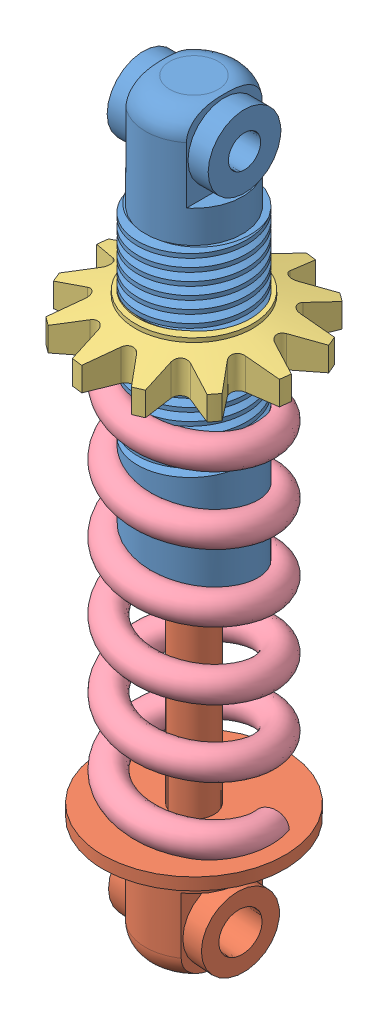
SolidWorks assembly shock absorber ass, configuration Default. Lengths in mm.
Overall size (66.19 187.81 66.19).
4 component instances, 4 part files, 6 mates.
Components (placement in the parent):
- top rod-1: top rod [Default] at (42.5756 -6.4521 89.0475) size (28.04 109.38 28.04)
- base-1: base [Default] at (42.5756 -56.4284 89.0475) x (0.997016 0 0.077201) z (-0.077201 0 0.997016) size (45 101.45 45)
- ring-1: ring [Default] at (42.5756 46.4716 89.0475) x (0.374524 0 -0.927217) z (0.927217 0 0.374524) size (50.85 11.86 50.85)
- spring-1: spring [Default] at (42.5756 46.4716 89.0475) x (0.946951 0 -0.321378) z (0.321378 0 0.946951) size (38.22 107.1 37.2)
Mates (geometry in assembly coordinates):
- Concentric1: concentric: cylinder of top rod-1 through (42.5756 68.5479 89.0475) axis (0 -1 0) radius 5; cylinder of ? through (42.5756 8.463 89.0475) axis (0 -1 0) radius 5
- Concentric2: concentric: cylinder of assembly; cylinder of assembly; cylinder of top rod-1 through (42.5756 74.4779 89.0475) axis (0 -1 0) radius 13.5; cylinder of ring-1 through (42.5756 56.4716 89.0475) axis (0 -1 0) radius 14.5
- Screw1: screw = 1: line of assembly; cylinder of assembly; axis of top rod-1 through (42.5756 74.4779 89.0475) axis (0 -1 0); cylinder of ring-1 through (42.5756 56.4716 89.0475) axis (0 -1 0) radius 14.5
- Concentric3: concentric: cylinder of assembly; line of assembly; cylinder of ring-1 through (42.5756 56.4716 89.0475) axis (0 -1 0) radius 14.5; line of spring-1 through (42.5756 46.4716 89.0475) axis (0 -1 0)
- Coincident5: coincident: line of assembly; plane of assembly; line of ring-1 through (59.5441 46.4716 97.7695) axis (0.615732 0 0.787956); plane of spring-1 through (42.5756 46.4716 89.0475) normal (0 1 0)
- Coincident6: coincident: circle of assembly; plane of assembly; circle of base-1; plane of spring-1 through (42.5756 -53.4284 89.0475) normal (0 -1 0)
